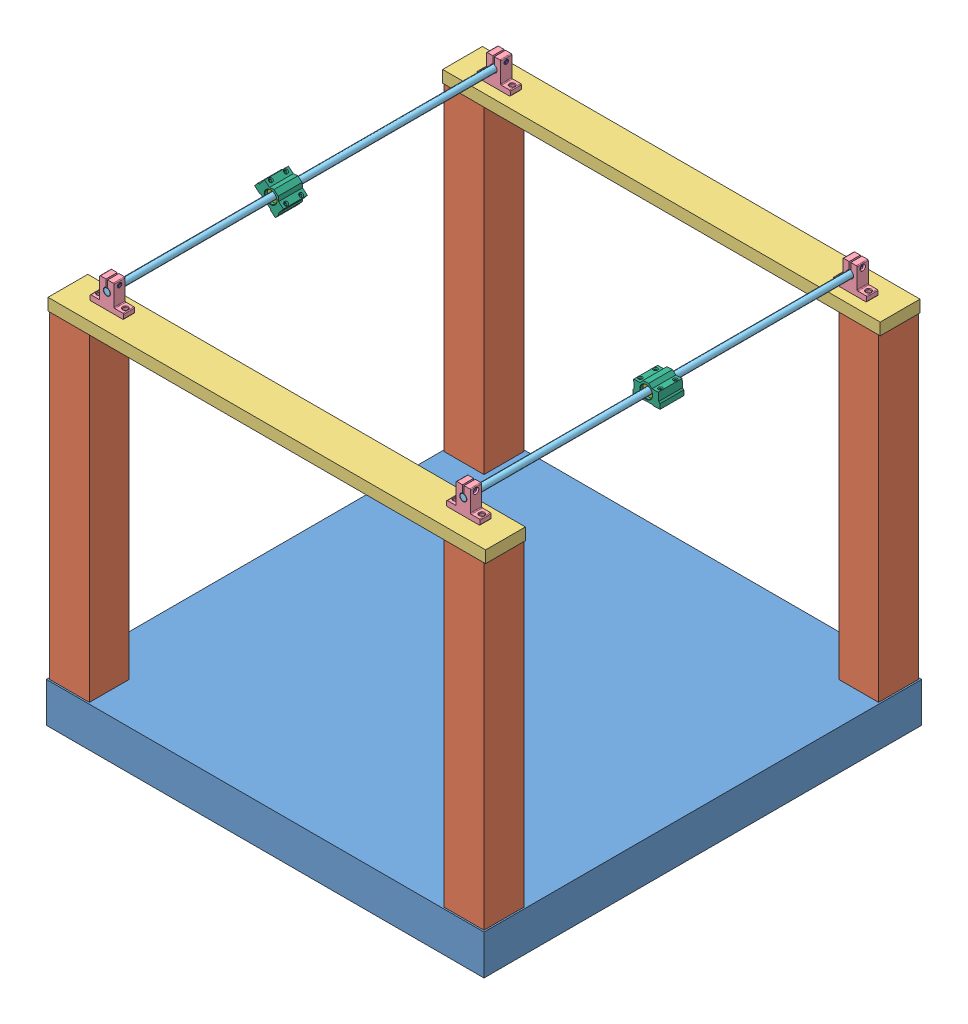
SolidWorks assembly Projektarbete1, configuration Default. Lengths in mm.
Overall size (550 504.16 550).
23 component instances, 8 part files, 46 mates.
Components (placement in the parent):
- Lack borskiva 55x55-1: Lack borskiva 55x55 [Default] at origin size (550 50 550)
- Lack Ben 5x55-1: Lack Ben 5x55 [Default] at (2 50 -2) size (50 400 50)
- Lack Ben 5x55-2: Lack Ben 5x55 [Default] at (2 50 -498) size (50 400 50)
- Lack Ben 5x55-3: Lack Ben 5x55 [Default] at (498 50 -498) size (50 400 50)
- Lack Ben 5x55-4: Lack Ben 5x55 [Default] at (498 50 -2) size (50 400 50)
- Planka-1: Planka [Default] at (0 450 -498) size (550 15 50)
- Planka-2: Planka [Default] at (0 450 -2) size (550 15 50)
- Stånghållare-1: Stånghållare [Default] at (499 485 -39) size (42 33.4 14)
- Stånghållare-2: Stånghållare [Default] at (499 485 -525) size (42 33.4 14)
- Stång 500mm-1: Stång 500mm [Default] at (499 485 -25) x (0 0 -1) z (-0.567878 0.823113 0) size (500 8 8)
- Stånghållare-5: Stånghållare [Default] at (51 485 -511) x (-1 0 0) z (0 0 -1) size (42 33.4 14)
- Stånghållare-6: Stånghållare [Default] at (51 485 -25) x (-1 0 0) z (0 0 -1) size (42 33.4 14)
- Stång 500mm-2: Stång 500mm [Default] at (51 485 -25) x (0 0 -1) z (1 0 0) size (500 8 8)
- Ball Bearing Assemby-2: Ball Bearing Assemby [Default] at (482.4782 473.294 -284.8808) x (0.999113 0.042103 0) z (0 0 1) size (34 21.75 30)
  - Ball Bearing Slider-1: Ball Bearing Slider [Default] at origin size (34 21.75 30)
  - Ball Bearing Imaginary Inlay-1: Ball Bearing Imaginary Inlay [Default] at (17 11 3.5) size (15 15 23)
- Ball Bearing Assemby-3: Ball Bearing Assemby [Default] at (30.9053 487.4908 -260.7773) x (0.766366 -0.642404 0) z (0 0 1) size (34 21.75 30)
  - Ball Bearing Slider-1: Ball Bearing Slider [Default] at origin size (34 21.75 30)
  - Ball Bearing Imaginary Inlay-1: Ball Bearing Imaginary Inlay [Default] at (17 11 3.5) size (15 15 23)
- Skruv_MK6SF_M4x14-2: Skruv_MK6SF_M4x14 [Default] at (43.2 493.2 -518) size (17.05 6.5 6.5)
- Skruv_MK6SF_M4x14-3: Skruv_MK6SF_M4x14 [Default] at (506.8 493.2 -518) x (-1 0 0) z (0 0.84457 0.535445) size (17.05 6.5 6.5)
- Skruv_MK6SF_M4x14-4: Skruv_MK6SF_M4x14 [Default] at (506.8 493.2 -32) x (-1 0 0) z (0 0.924225 0.381849) size (17.05 6.5 6.5)
- Skruv_MK6SF_M4x14-5: Skruv_MK6SF_M4x14 [Default] at (43.2 493.2 -32) size (17.05 6.5 6.5)
Mates (geometry in assembly coordinates):
- Coincident1: coincident: plane of Lack borskiva 55x55-1 through (0 50 0) normal (0 1 0); plane of Lack Ben 5x55-1 through (2 50 -2) normal (0 -1 0)
- Coincident2: coincident: plane of Lack borskiva 55x55-1 through (0 50 0) normal (0 1 0); plane of Lack Ben 5x55-2 through (2 50 -498) normal (0 -1 0)
- Coincident3: coincident: plane of Lack borskiva 55x55-1 through (0 50 0) normal (0 1 0); plane of Lack Ben 5x55-3 through (498 50 -498) normal (0 -1 0)
- Coincident4: coincident: plane of Lack borskiva 55x55-1 through (0 50 0) normal (0 1 0); plane of Lack Ben 5x55-4 through (498 50 -2) normal (0 -1 0)
- Distance1: distance = 2 mm: line of Lack Ben 5x55-1 through (2 50 -2) axis (1 0 0); line of Lack borskiva 55x55-1 through (550 0 50) axis (0 1 0)
- Distance2: distance = 2 mm: line of Lack Ben 5x55-1 through (2 50 -52) axis (0 0 1); line of Lack borskiva 55x55-1 through (0 50 -550) axis (0 0 1)
- Distance4: distance = 2 mm: line of Lack borskiva 55x55-1 through (550 0 50) axis (0 1 0); line of Lack Ben 5x55-4 through (498 50 -2) axis (1 0 0)
- Distance3: distance = 2 mm: line of Lack Ben 5x55-4 through (548 50 -2) axis (0 0 -1); line of Lack borskiva 55x55-1 through (550 50 0) axis (0 0 -1)
- Distance5: distance = 2 mm: line of Lack Ben 5x55-3 through (548 50 -498) axis (0 0 -1); line of Lack borskiva 55x55-1 through (550 50 0) axis (0 0 -1)
- Distance6: distance = 2 mm: line of Lack Ben 5x55-3 through (548 50 -548) axis (-1 0 0); line of Lack borskiva 55x55-1 through (550 50 -550) axis (-1 0 0)
- Distance7: distance = 2 mm: line of Lack Ben 5x55-2 through (52 50 -548) axis (-1 0 0); line of Lack borskiva 55x55-1 through (550 50 -550) axis (-1 0 0)
- Distance8: distance = 2 mm: line of Lack Ben 5x55-2 through (2 50 -548) axis (0 0 1); line of Lack borskiva 55x55-1 through (0 50 -550) axis (0 0 1)
- Coincident14: coincident: plane of Lack Ben 5x55-1 through (2 450 -2) normal (0 1 0); plane of Planka-2 through (0 450 -2) normal (0 -1 0)
- Coincident15: coincident: line of Lack Ben 5x55-1 through (2 450 -2) axis (1 0 0); line of Planka-2 through (0 450 -2) axis (1 0 0)
- Distance9: distance = 2 mm: line of Planka-2 through (0 450 -52) axis (0 0 1); line of Lack Ben 5x55-1 through (2 450 -52) axis (0 0 1)
- Coincident17: coincident: plane of Lack Ben 5x55-2 through (2 450 -498) normal (0 1 0); plane of Planka-1 through (0 450 -498) normal (0 -1 0)
- Coincident18: coincident: line of Lack Ben 5x55-2 through (2 450 -498) axis (1 0 0); line of Planka-1 through (0 450 -498) axis (1 0 0)
- Distance10: distance = 2 mm: line of Planka-1 through (0 450 -548) axis (0 0 1); line of Lack Ben 5x55-2 through (2 450 -548) axis (0 0 1)
- Distance11: distance = 31 mm: line of Planka-2 through (550 465 -2) axis (0 0 -1); line of Stånghållare-1 through (519 465 -39) axis (0 0 1)
- Coincident22: coincident: plane of Planka-2 through (0 465 -2) normal (0 1 0); plane of Stånghållare-1 through (478 465 -25) normal (0 -1 0)
- Distance12: distance = 13 mm: line of Stånghållare-1 through (479 465 -39) axis (1 0 0); line of Planka-2 through (550 465 -52) axis (-1 0 0)
- Distance13: distance = 31 mm: line of Planka-1 through (550 465 -498) axis (0 0 -1); line of Stånghållare-2 through (519 465 -525) axis (0 0 1)
- Coincident26: coincident: plane of Planka-1 through (0 465 -498) normal (0 1 0); plane of Stånghållare-2 through (478 465 -511) normal (0 -1 0)
- Distance14: distance = 13 mm: line of Stånghållare-2 through (479 465 -511) axis (1 0 0); line of Planka-1 through (0 465 -498) axis (1 0 0)
- Concentric2: concentric: circle of Stånghållare-1; circle of Stång 500mm-1
- Coincident33: coincident: plane of Stånghållare-1 through (499 485 -25) normal (0 0 1); plane of Stång 500mm-1 through (499 485 -25) normal (0 0 1)
- Distance16: distance = 31 mm: line of Stånghållare-5 through (31 465 -511) axis (0 0 -1); line of Planka-1 through (0 465 -548) axis (0 0 1)
- Coincident35: coincident: plane of Planka-1 through (0 465 -498) normal (0 1 0); plane of Stånghållare-5 through (72 465 -525) normal (0 -1 0)
- Distance17: distance = 13 mm: line of Stånghållare-5 through (71 465 -511) axis (-1 0 0); line of Planka-1 through (0 465 -498) axis (1 0 0)
- Coincident37: coincident: plane of Planka-2 through (0 465 -2) normal (0 1 0); plane of Stånghållare-6 through (72 465 -39) normal (0 -1 0)
- Distance18: distance = 31 mm: line of Planka-2 through (0 465 -52) axis (0 0 1); line of Stånghållare-6 through (31 465 -25) axis (0 0 -1)
- Distance19: distance = 13 mm: line of Stånghållare-6 through (71 465 -39) axis (-1 0 0); line of Planka-2 through (550 465 -52) axis (-1 0 0)
- Concentric4: concentric: circle of Stånghållare-5; circle of Stång 500mm-2
- Coincident41: coincident: plane of Stånghållare-6 through (51 485 -25) normal (0 0 1); plane of Stång 500mm-2 through (51 485 -25) normal (0 0 1)
- Concentric5: concentric: cylinder of Stång 500mm-1 through (499 485 -525) axis (0 0 1) radius 4; cylinder of Ball Bearing Assemby-2/Ball Bearing Imaginary Inlay-1 through (499 485 -281.3808) axis (0 0 1) radius 4.05
- LimitDistance1: limit distance = 259.8808 mm: plane of Stång 500mm-1 through (499 485 -25) normal (0 0 -1); plane of Ball Bearing Assemby-2/Ball Bearing Slider-1 through (482.4782 473.294 -284.8808) normal (0 0 1)
- Concentric6: concentric: cylinder of Stång 500mm-2 through (51 485 -525) axis (0 0 1) radius 4; cylinder of Ball Bearing Assemby-3/Ball Bearing Imaginary Inlay-1 through (51 485 -257.2773) axis (0 0 1) radius 4.05
- LimitDistance2: limit distance = 235.7773 mm: plane of Stång 500mm-2 through (51 485 -25) normal (0 0 -1); plane of Ball Bearing Assemby-3/Ball Bearing Slider-1 through (30.9053 487.4908 -260.7773) normal (0 0 1)
- Concentric81: concentric: cylinder of Stånghållare-5 through (42 493.2 -518) axis (-1 0 0) radius 2; cylinder of Skruv_MK6SF_M4x14-2 through (43.2 493.2 -518) axis (-1 0 0) radius 3.25
- Coincident451: coincident: plane of Stånghållare-5 through (46.5 495.2 -518) normal (-1 0 0); plane of Skruv_MK6SF_M4x14-2 through (46.5 495.2 -518) normal (1 0 0)
- Concentric91: concentric: cylinder of Stånghållare-2 through (508 493.2 -518) axis (1 0 0) radius 3.5; cylinder of Skruv_MK6SF_M4x14-3 through (506.8 493.2 -518) axis (1 0 0) radius 3.25
- Coincident461: coincident: plane of Stånghållare-2 through (503.5 495.2 -518) normal (1 0 0); plane of Skruv_MK6SF_M4x14-3 through (503.5 492.1291 -516.3109) normal (-1 0 0)
- Concentric101: concentric: cylinder of Stånghållare-1 through (508 493.2 -32) axis (1 0 0) radius 2; cylinder of Skruv_MK6SF_M4x14-4 through (506.8 493.2 -32) axis (1 0 0) radius 3.25
- Coincident471: coincident: plane of Stånghållare-1 through (503.5 495.2 -32) normal (1 0 0); plane of Skruv_MK6SF_M4x14-4 through (503.5 492.4363 -30.1516) normal (-1 0 0)
- Concentric111: concentric: cylinder of Stånghållare-6 through (42 493.2 -32) axis (-1 0 0) radius 2; cylinder of Skruv_MK6SF_M4x14-5 through (43.2 493.2 -32) axis (-1 0 0) radius 3.25
- Coincident481: coincident: plane of Stånghållare-6 through (46.5 495.2 -32) normal (-1 0 0); plane of Skruv_MK6SF_M4x14-5 through (46.5 495.2 -32) normal (1 0 0)
